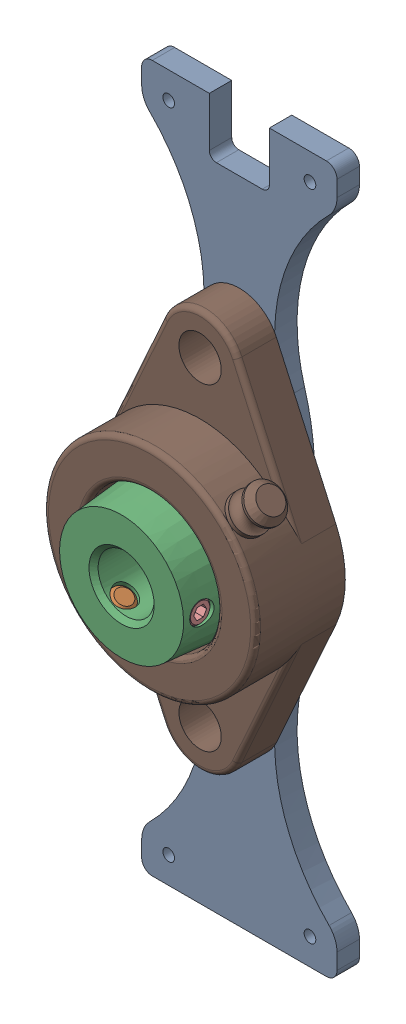
SolidWorks assembly Bearing Bar Subassembly-2023, configuration Default. Lengths in mm.
Overall size (60.31 200 39.69).
2 component instances, 2 part files, 3 mates.
Components (placement in the parent):
- Bearing Bar-2023-1: Bearing Bar-2023 [Default] at origin size (55.3 200 6.35)
- 6494K38_Mounted Ball Bearing with Nickel-Plated Iron Housing-2023-1: 6494K38_Mounted Ball Bearing with Nickel-Plated Iron Housing-2023 [6494K38] at (0 0 6.35) x (0 -1 0) z (0 0 1) size (112.98 60.31 33.34)
Mates (geometry in assembly coordinates):
- Concentric1: concentric aligned: cylinder of Bearing Bar-1 through (0 0 6.35) axis (0 0 -1) radius 9; cylinder of 6494K38_Mounted Ball Bearing with Nickel-Plated Iron Housing-1 through (0 0 6.35) axis (0 0 -1) radius 7.9375
- Concentric2: concentric aligned: cylinder of Bearing Bar-1 through (0 44.9961 6.35) axis (0 0 -1) radius 3; cylinder of 6494K38_Mounted Ball Bearing with Nickel-Plated Iron Housing-1 through (0 44.9961 17.4625) axis (0 0 -1) radius 5.9944
- Coincident1: coincident anti-aligned: plane of Bearing Bar-1 through (20 -92.5 6.35) normal (0 0 1); plane of 6494K38_Mounted Ball Bearing with Nickel-Plated Iron Housing-1 through (0 -44.9961 6.35) normal (0 0 -1)
